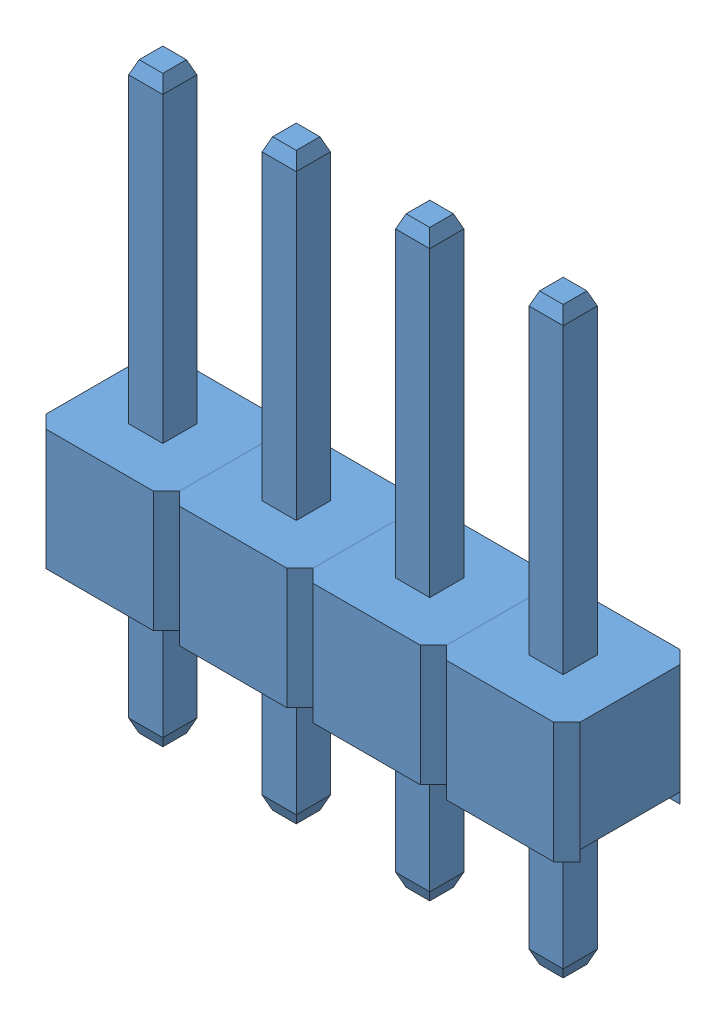
SolidWorks assembly 4x_Male_Pin_2.54_mm, configuration Default. Lengths in mm.
Overall size (10.16 11.1 2.4).
5 component instances, 1 part files, 0 mates.
Components (placement in the parent):
- 4x_Male_Pin_2.54_mm.STEP-1: 4x_Male_Pin_2.54_mm.STEP [Default] at origin size (10.16 11.1 2.4)
  - 1_Male_Pin_2.54_mm.STEP-1: 1_Male_Pin_2.54_mm.STEP [Default] at (3.8763 2.2562 11.0637) size (2.54 11.1 2.4)
  - 1_Male_Pin_2.54_mm.STEP-2: 1_Male_Pin_2.54_mm.STEP [Default] at (1.3363 2.2562 11.0637) size (2.54 11.1 2.4)
  - 1_Male_Pin_2.54_mm.STEP-3: 1_Male_Pin_2.54_mm.STEP [Default] at (-1.2037 2.2562 11.0637) size (2.54 11.1 2.4)
  - 1_Male_Pin_2.54_mm.STEP-4: 1_Male_Pin_2.54_mm.STEP [Default] at (-3.7437 2.2562 11.0637) size (2.54 11.1 2.4)
